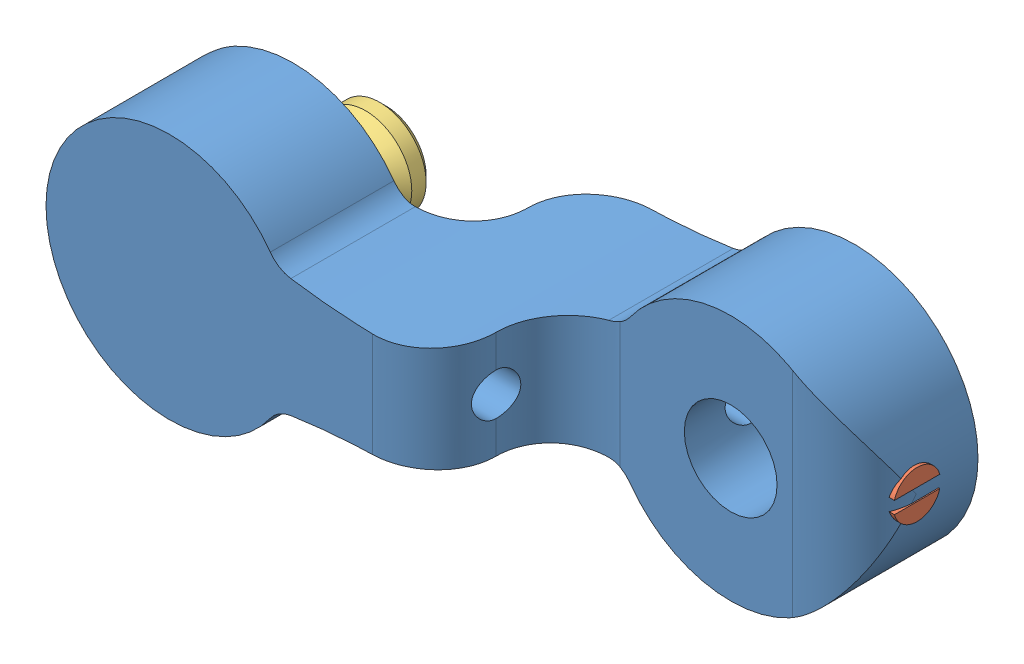
SolidWorks assembly 500-Link, configuration Default. Lengths in mm.
Overall size (70.42 25.4 25.4).
4 component instances, 3 part files, 9 mates.
Components (placement in the parent):
- 501-Link-2: 501-Link [Default] at origin size (70.32 25.4 25.4)
- 507-SSBallNoseSpringPlunger_MC-3408A95-1: 507-SSBallNoseSpringPlunger_MC-3408A95 [Default] at (22.225 0 0) x (0 0 -1) z (1 0 0) size (4.83 4.83 13.67)
- 505-ShaftSwivel-1: 505-ShaftSwivel [Default] at (0 0 11.43) x (-1 0 0) z (0 0 -1) size (9.5 9.5 19.05)
- 507-SSBallNoseSpringPlunger_MC-3408A95-3: 507-SSBallNoseSpringPlunger_MC-3408A95 [Default] at (-17.7078 -1.2537 12.575) x (0 0.197431 -0.980317) z (1 0 0) size (4.83 4.83 13.67)
Mates (geometry in assembly coordinates):
- InPlace1: in place: plane of 501-Link-2 through (22.225 0 0) normal (1 0 0); unknown of 507-SSBallNoseSpringPlunger_MC-3408A95-1
- Coincident1: coincident aligned: plane of ?; plane of ?
- Coincident2: coincident aligned: moOrthogonalPlaneRef_w of ?; plane of ?
- Coincident3: coincident anti-aligned: moOrthogonalPlaneRef_w of ?; plane of ?
- InPlace3: in place: unknown of 501-Link-2; unknown of 505-ShaftSwivel-1
- Coincident1: coincident aligned: plane of ?; plane of ?
- Coincident2: coincident aligned: moOrthogonalPlaneRef_w of ?; plane of ?
- Coincident3: coincident anti-aligned: moOrthogonalPlaneRef_w of ?; plane of ?
- Concentric1: concentric aligned: cylinder of 501-Link-2; cylinder of 507-SSBallNoseSpringPlunger_MC-3408A95-3
